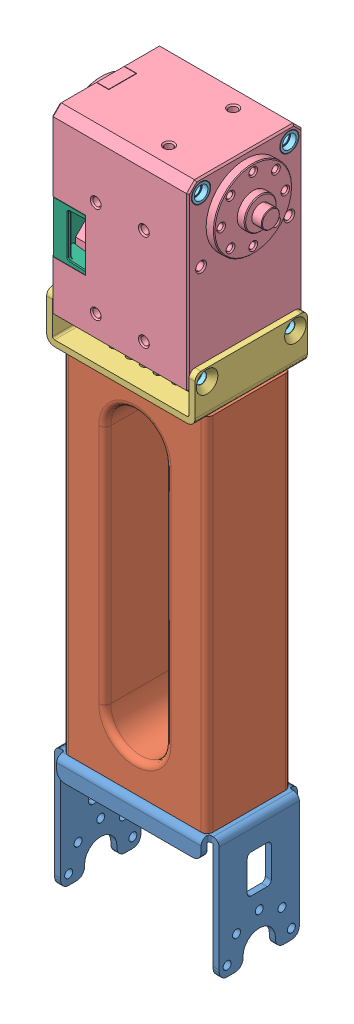
SolidWorks assembly link4, configuration 기본. Lengths in mm.
Overall size (43.9 172.25 28.5).
14 component instances, 6 part files, 9 mates.
Components (placement in the parent):
- fr12_h101-1: fr12_h101 [기본] at (-2.5744 -12.4757 41) size (41 30.5 24)
- linkframe2-1: linkframe2 [기본] at (-2.5744 15.5243 41) x (1 0 0) z (0 1 0) size (36 21 90)
- fr12_s102-1: fr12_s102 [기본] at (-2.5744 125.0243 41) x (1 0 0) z (0 -1 0) size (37 28 11.5)
- x-430_idle-1: x-430_idle [기본] at (-2.5744 146.0243 41) x (0 0 -1) z (1 0 0) size (28.5 46.5 42.4)
  - X-430_IDLE-1: X-430_IDLE [기본] at origin size (28.5 46.5 42.4)
  - X-430_SPACER_RING-1: X-430_SPACER_RING [기본] at (11 8 14.2) x (-1 0 0) z (0 1 0) size (4.8 2.8 4.8)
  - X-430_SPACER_RING-2: X-430_SPACER_RING [기본] at (-11 8 14.2) x (-1 0 0) z (0 1 0) size (4.8 2.8 4.8)
  - X-430_SPACER_RING-3: X-430_SPACER_RING [기본] at (11 -32 14.2) x (-1 0 0) z (0 1 0) size (4.8 2.8 4.8)
  - X-430_SPACER_RING-4: X-430_SPACER_RING [기본] at (-11 -32 14.2) x (-1 0 0) z (0 1 0) size (4.8 2.8 4.8)
  - X-430_SPACER_RING-5: X-430_SPACER_RING [기본] at (-11 8 -14.2) x (1 0 0) z (0 1 0) size (4.8 2.8 4.8)
  - X-430_SPACER_RING-6: X-430_SPACER_RING [기본] at (11 8 -14.2) x (1 0 0) z (0 1 0) size (4.8 2.8 4.8)
  - X-430_SPACER_RING-7: X-430_SPACER_RING [기본] at (-11 -32 -14.2) x (1 0 0) z (0 1 0) size (4.8 2.8 4.8)
  - X-430_SPACER_RING-8: X-430_SPACER_RING [기본] at (11 -32 -14.2) x (1 0 0) z (0 1 0) size (4.8 2.8 4.8)
  - X-430_CVR_CABLE-1: X-430_CVR_CABLE [기본] at origin size (28.5 12.8 8.8)
Mates (geometry in assembly coordinates):
- 일치1: coincident anti-aligned: plane of fr12_h101-1 through (-21.5744 15.5243 51) normal (0 1 0); plane of linkframe2-1 through (-2.5744 15.5243 41) normal (0 -1 0)
- 일치3: coincident aligned: circle of fr12_h101-1; circle of linkframe2-1
- 동심2: concentric anti-aligned: circle of fr12_h101-1; circle of linkframe2-1
- 일치5: coincident anti-aligned: plane of linkframe2-1 through (-2.5744 105.5243 41) normal (0 1 0); plane of fr12_s102-1 through (13.9256 105.5243 27) normal (0 -1 0)
- 동심3: concentric aligned: circle of linkframe2-1; circle of fr12_s102-1
- 동심4: concentric aligned: circle of linkframe2-1; circle of fr12_s102-1
- 동심5: concentric anti-aligned: circle of fr12_s102-1; circle of x-430_idle-1/X-430_SPACER_RING-4
- 동심6: concentric anti-aligned: circle of fr12_s102-1; circle of x-430_idle-1/X-430_SPACER_RING-3
- 너비1: width aligned: plane of fr12_s102-1 through (-19.5744 107.5243 27) normal (1 0 0); plane of fr12_s102-1 through (14.4256 117.0243 27) normal (-1 0 0); plane of x-430_idle-1/X-430_IDLE-1 through (14.4256 146.0243 41) normal (1 0 0); plane of x-430_idle-1/X-430_IDLE-1 through (-19.5744 146.0243 41) normal (-1 0 0)
